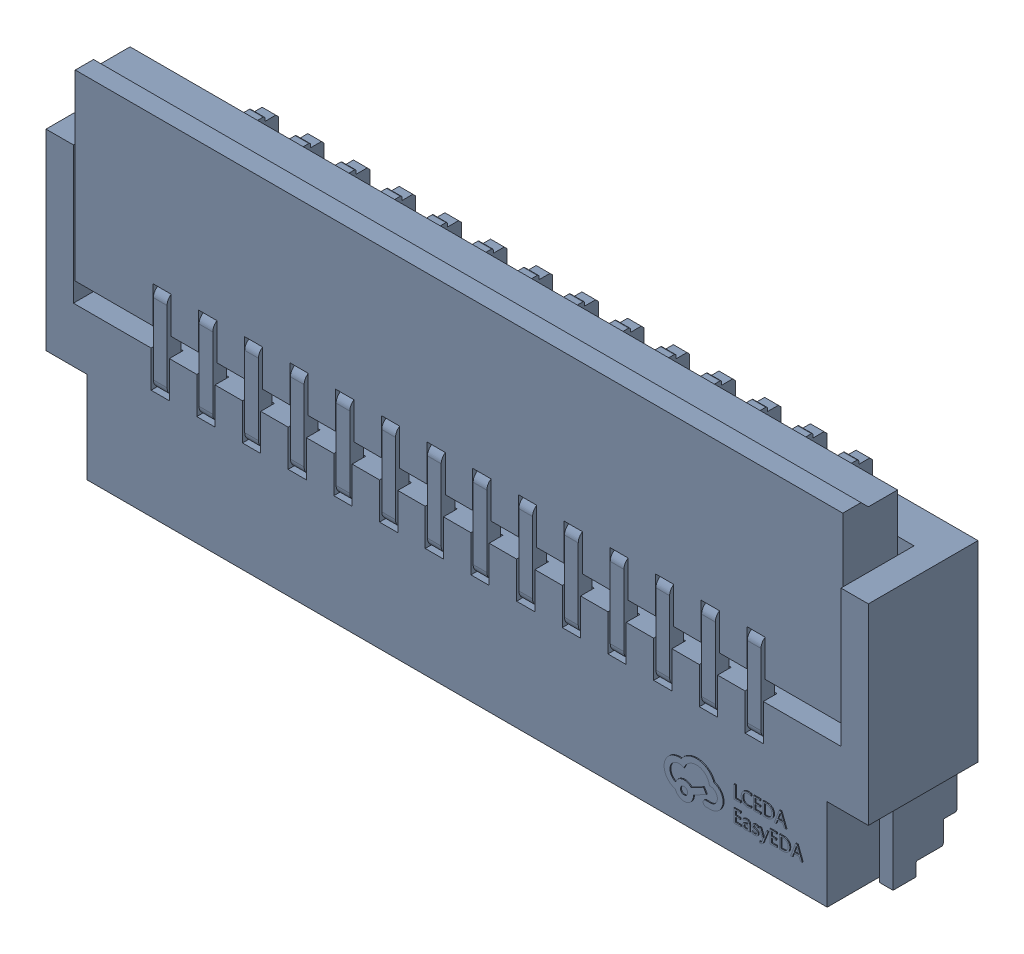
SolidWorks assembly FH34SRJ-14S-0.5SH(50), configuration Défaut. Lengths in mm.
Overall size (9 3.8 1.23).
3 component instances, 1 part files, 0 mates.
Components (placement in the parent):
- FPC1.step-1: FPC1.step [Défaut] at (8.84 -9.4501 1.6001) size (9 3.8 1.23)
  - FFC-SMD_14P-P0.50_FH34SRJ-14S-0.5SH.step-1: FFC-SMD_14P-P0.50_FH34SRJ-14S-0.5SH.step [Défaut] at origin size (9 3.8 1.23)
    - SOLID.step-1: SOLID.step [Défaut] at origin size (9 3.8 1.23)
